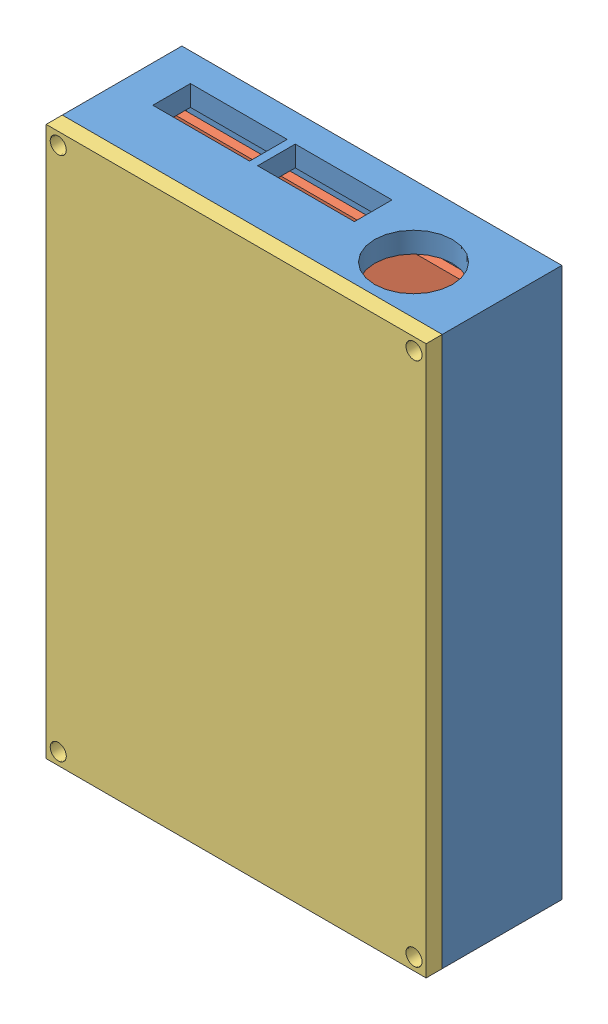
SolidWorks assembly Assem1, configuration Default. Lengths in mm.
Overall size (70.68 102.18 25.25).
3 component instances, 3 part files, 6 mates.
Components (placement in the parent):
- PCB_Pad-1: PCB_Pad [Default] at (-41.221 -49.3036 -6.7623) size (70.68 102.18 22.25)
- PCB-1: PCB [Default] at (-36.285 49.0374 -3.5123) x (0 -1 0) z (0 0 1) size (91.5 60.32 1.65)
- FacePlate-1: FacePlate [Default] at (-41.221 -49.3036 12.4877) size (70.68 102.18 17.35)
Mates (geometry in assembly coordinates):
- Coincident3: coincident anti-aligned: plane of PCB_Pad-1 through (-41.221 -49.3036 -3.5123) normal (0 0 1); plane of PCB-1 through (-36.285 49.0374 -3.5123) normal (0 0 -1)
- Coincident4: coincident anti-aligned: plane of PCB_Pad-1 through (-41.221 49.0374 12.4877) normal (0 -1 0); plane of PCB-1 through (-36.285 49.0374 -1.8623) normal (0 1 0)
- Coincident5: coincident: plane of PCB_Pad-1 through (-34.38 73.3845 -4.5123) normal (1 0 0); line of PCB-1 through (-34.38 49.0374 -3.5123) axis (0 -1 0)
- Coincident6: coincident anti-aligned: plane of PCB-1 through (-36.285 49.0374 -1.8623) normal (0 0 1); plane of FacePlate-1 through (-41.221 -49.3036 -1.8623) normal (0 0 -1)
- Coincident7: coincident aligned: plane of PCB_Pad-1 through (-41.221 52.8784 -9.7623) normal (0 1 0); plane of FacePlate-1 through (-41.221 52.8784 15.4877) normal (0 1 0)
- Coincident8: coincident: plane of PCB_Pad-1 through (29.461 -49.3036 -9.7623) normal (1 0 0); line of FacePlate-1 through (29.461 -49.3036 12.4877) axis (0 1 0)
